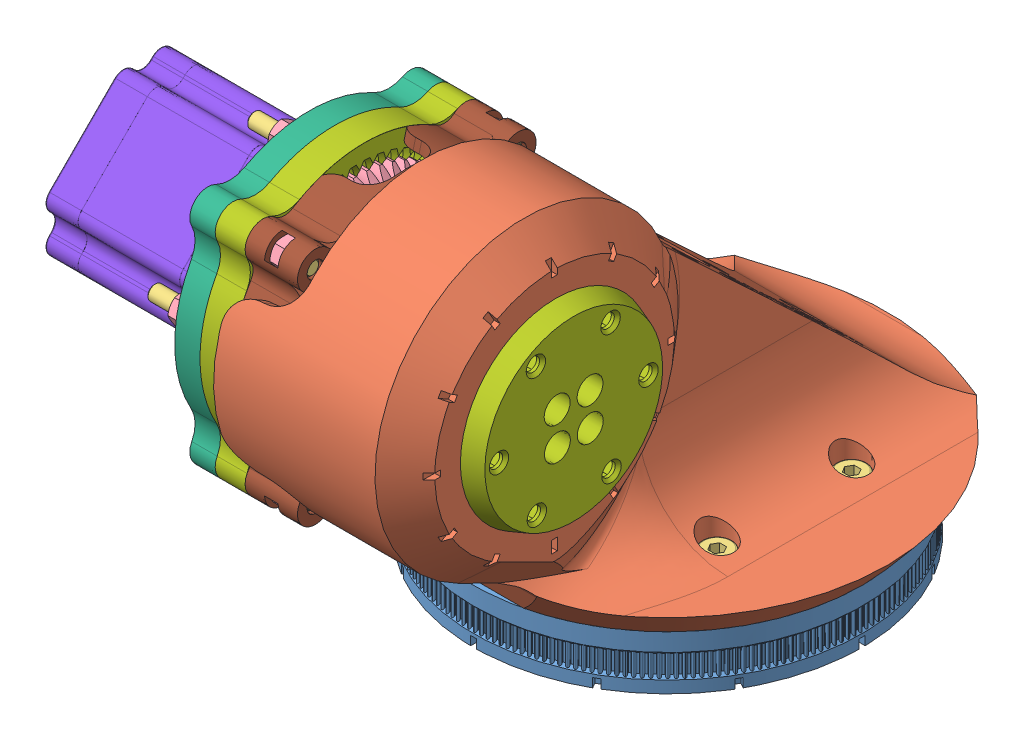
SolidWorks assembly Gelenk_0, configuration Standard. Lengths in mm.
Overall size (179.39 138.2 193.39).
141 component instances, 43 part files, 23 mates.
Components (placement in the parent):
- Base_Arm-1: Base_Arm [Standard] at origin size (130 18.2 130)
- Halterung_Base_Arm-1: Halterung_Base_Arm [Standard] at (0 18 0) size (146.78 120 193.39)
- socket head thin cap screw_din-2: socket head thin cap screw_din [DIN 7984 - M6 x 20 --- 17N] at (-38.9711 27 22.5) x (0 -1 0) z (0 0 1) size (24 10 10)
- hex nut style 1 gradeab_din-1: hex nut style 1 gradeab_din [Hexagon Nut ISO 4032 - M6 - W - N] at (-38.9711 10 22.5) x (1 0 0) z (0 1 0) size (10 11.55 5.2)
- socket head thin cap screw_din-3: socket head thin cap screw_din [DIN 7984 - M6 x 20 --- 17N] at (-38.9711 27 -22.5) x (0 -1 0) z (-0.866025 0 0.5) size (24 10 10)
- socket head thin cap screw_din-4: socket head thin cap screw_din [DIN 7984 - M6 x 20 --- 17N] at (0 27 -45) x (0 -1 0) z (-0.866025 0 -0.5) size (24 10 10)
- socket head thin cap screw_din-5: socket head thin cap screw_din [DIN 7984 - M6 x 20 --- 17N] at (38.9711 27 -22.5) x (0 -1 0) z (0 0 -1) size (24 10 10)
- socket head thin cap screw_din-6: socket head thin cap screw_din [DIN 7984 - M6 x 20 --- 17N] at (38.9711 27 22.5) x (0 -1 0) z (0.866025 0 -0.5) size (24 10 10)
- hex nut style 1 gradeab_din-2: hex nut style 1 gradeab_din [Hexagon Nut ISO 4032 - M6 - W - N] at (-38.9711 10 -22.5) x (0.5 0 0.866025) z (0 1 0) size (10 11.55 5.2)
- hex nut style 1 gradeab_din-3: hex nut style 1 gradeab_din [Hexagon Nut ISO 4032 - M6 - W - N] at (0 10 -45) x (-0.5 0 0.866025) z (0 1 0) size (10 11.55 5.2)
- hex nut style 1 gradeab_din-4: hex nut style 1 gradeab_din [Hexagon Nut ISO 4032 - M6 - W - N] at (38.9711 10 -22.5) x (-1 0 0) z (0 1 0) size (10 11.55 5.2)
- hex nut style 1 gradeab_din-5: hex nut style 1 gradeab_din [Hexagon Nut ISO 4032 - M6 - W - N] at (38.9711 10 22.5) x (-0.5 0 -0.866025) z (0 1 0) size (10 11.55 5.2)
- hex nut style 1 gradeab_din-6: hex nut style 1 gradeab_din [Hexagon Nut ISO 4032 - M3 - W - N] at (12.4 103.5 54.5) x (0 0 -1) z (1 0 0) size (5.5 6.35 2.4)
- radial ball bearing_68_din-1: radial ball bearing_68_din [DIN 625 - 6206 - 12,SI,NC,12_68] at (24 88 70) size (16 62 62)
- Strain_Wave_Base_Finale-1: Strain_Wave_Base_Finale [Standard] at (-50 88 70) x (0 0 1) z (-1 0 0) size (99.02 99.01 139) (flexible)
  - Circular_Spline-1: Circular_Spline [Standard] at origin size (90 90 8.5)
  - Circular_Spline_Teeth-1: Circular_Spline_Teeth [Standard] at (0 0 -12) size (90 90 11.5)
  - Nema_23_56mm-1: Nema_23_56mm [Standard] at (0 0 56) x (0.707107 0.707107 0) z (0 0 -1) size (72.51 57.02 77)
  - Wave_Generator-1: Wave_Generator [Standard] at (0 0 -22.5) size (51.83 63.24 19)
    - Wave_Generator-1: Wave_Generator [Standard] at origin size (49.88 60 10)
    - socket head thin cap screw_din-1: socket head thin cap screw_din [DIN 7984 - M3 x 16 --- 14.5N] at (0 26.62 1) x (0 0 1) z (-1 0 0) size (18 5.5 5.5)
    - socket head thin cap screw_din-2: socket head thin cap screw_din [DIN 7984 - M3 x 16 --- 14.5N] at (11.5 22.98 1) x (0 0 1) z (-1 0 0) size (18 5.5 5.5)
    - socket head thin cap screw_din-3: socket head thin cap screw_din [DIN 7984 - M3 x 16 --- 14.5N] at (19 14.3 1) x (0 0 1) z (-1 0 0) size (18 5.5 5.5)
    - radial ball bearing_68_din-2: radial ball bearing_68_din [DIN 625 - 623 - 8,SI,NC,8_68] at (11.5 22.98 8) x (0 0 -1) z (1 0 0) size (4 10 10)
    - radial ball bearing_68_din-3: radial ball bearing_68_din [DIN 625 - 623 - 8,SI,NC,8_68] at (19 14.3 8) x (0 0 -1) z (1 0 0) size (4 10 10)
    - radial ball bearing_68_din-4: radial ball bearing_68_din [DIN 625 - 623 - 8,SI,NC,8_68] at (0 26.62 8) x (0 0 -1) z (1 0 0) size (4 10 10)
    - Wave_Generator_Case-1: Wave_Generator_Case [Standard] at (0 0 17.5) x (-1 0 0) z (0 0 -1) size (51.83 61 3.5)
    - hex nut style 1 gradeab_din-2: hex nut style 1 gradeab_din [Hexagon Nut ISO 4032 - M3 - W - N] at (0 26.62 17.65) size (5.5 6.35 2.4)
    - hex nut style 1 gradeab_din-3: hex nut style 1 gradeab_din [Hexagon Nut ISO 4032 - M3 - W - N] at (11.5 22.98 17.65) size (5.5 6.35 2.4)
    - hex nut style 1 gradeab_din-4: hex nut style 1 gradeab_din [Hexagon Nut ISO 4032 - M3 - W - N] at (19 14.3 17.65) size (5.5 6.35 2.4)
    - socket head thin cap screw_din-4: socket head thin cap screw_din [DIN 7984 - M3 x 16 --- 14.5N] at (-11.5 22.98 1) x (0 0 1) z (-1 0 0) size (18 5.5 5.5)
    - radial ball bearing_68_din-5: radial ball bearing_68_din [DIN 625 - 623 - 8,SI,NC,8_68] at (-11.5 22.98 8) x (0 0 -1) z (1 0 0) size (4 10 10)
    - hex nut style 1 gradeab_din-5: hex nut style 1 gradeab_din [Hexagon Nut ISO 4032 - M3 - W - N] at (-11.5 22.98 17.65) size (5.5 6.35 2.4)
    - radial ball bearing_68_din-6: radial ball bearing_68_din [DIN 625 - 623 - 8,SI,NC,8_68] at (-19 14.3 8) x (0 0 -1) z (1 0 0) size (4 10 10)
    - hex nut style 1 gradeab_din-6: hex nut style 1 gradeab_din [Hexagon Nut ISO 4032 - M3 - W - N] at (-19 14.3 17.65) size (5.5 6.35 2.4)
    - socket head thin cap screw_din-5: socket head thin cap screw_din [DIN 7984 - M3 x 16 --- 14.5N] at (-19 14.3 1) x (0 0 1) z (-1 0 0) size (18 5.5 5.5)
    - socket head thin cap screw_din-6: socket head thin cap screw_din [DIN 7984 - M3 x 16 --- 14.5N] at (11.5 -22.98 1) x (0 0 1) z (1 0 0) size (18 5.5 5.5)
    - radial ball bearing_68_din-7: radial ball bearing_68_din [DIN 625 - 623 - 8,SI,NC,8_68] at (11.5 -22.98 8) x (0 0 -1) z (-1 0 0) size (4 10 10)
    - hex nut style 1 gradeab_din-7: hex nut style 1 gradeab_din [Hexagon Nut ISO 4032 - M3 - W - N] at (11.5 -22.98 17.65) x (-1 0 0) z (0 0 1) size (5.5 6.35 2.4)
    - radial ball bearing_68_din-8: radial ball bearing_68_din [DIN 625 - 623 - 8,SI,NC,8_68] at (19 -14.3 8) x (0 0 -1) z (-1 0 0) size (4 10 10)
    - hex nut style 1 gradeab_din-8: hex nut style 1 gradeab_din [Hexagon Nut ISO 4032 - M3 - W - N] at (19 -14.3 17.65) x (-1 0 0) z (0 0 1) size (5.5 6.35 2.4)
    - socket head thin cap screw_din-7: socket head thin cap screw_din [DIN 7984 - M3 x 16 --- 14.5N] at (19 -14.3 1) x (0 0 1) z (1 0 0) size (18 5.5 5.5)
    - socket head thin cap screw_din-8: socket head thin cap screw_din [DIN 7984 - M3 x 16 --- 14.5N] at (-11.5 -22.98 1) x (0 0 1) z (1 0 0) size (18 5.5 5.5)
    - radial ball bearing_68_din-9: radial ball bearing_68_din [DIN 625 - 623 - 8,SI,NC,8_68] at (-11.5 -22.98 8) x (0 0 -1) z (-1 0 0) size (4 10 10)
    - hex nut style 1 gradeab_din-9: hex nut style 1 gradeab_din [Hexagon Nut ISO 4032 - M3 - W - N] at (-11.5 -22.98 17.65) x (-1 0 0) z (0 0 1) size (5.5 6.35 2.4)
    - radial ball bearing_68_din-10: radial ball bearing_68_din [DIN 625 - 623 - 8,SI,NC,8_68] at (-19 -14.3 8) x (0 0 -1) z (-1 0 0) size (4 10 10)
    - hex nut style 1 gradeab_din-10: hex nut style 1 gradeab_din [Hexagon Nut ISO 4032 - M3 - W - N] at (-19 -14.3 17.65) x (-1 0 0) z (0 0 1) size (5.5 6.35 2.4)
    - socket head thin cap screw_din-9: socket head thin cap screw_din [DIN 7984 - M3 x 16 --- 14.5N] at (-19 -14.3 1) x (0 0 1) z (1 0 0) size (18 5.5 5.5)
    - socket head thin cap screw_din-10: socket head thin cap screw_din [DIN 7984 - M3 x 16 --- 14.5N] at (0 -26.62 1) x (0 0 1) z (1 0 0) size (18 5.5 5.5)
    - hex nut style 1 gradeab_din-11: hex nut style 1 gradeab_din [Hexagon Nut ISO 4032 - M3 - W - N] at (0 -26.62 17.65) x (-1 0 0) z (0 0 1) size (5.5 6.35 2.4)
    - radial ball bearing_68_din-11: radial ball bearing_68_din [DIN 625 - 623 - 8,SI,NC,8_68] at (0 -26.62 8) x (0 0 -1) z (-1 0 0) size (4 10 10)
    - radial ball bearing_68_din-13: radial ball bearing_68_din [DIN 625 - 623 - 8,SI,NC,8_68] at (11.5 22.98 12) x (0 0 -1) z (1 0 0) size (4 10 10)
    - radial ball bearing_68_din-14: radial ball bearing_68_din [DIN 625 - 623 - 8,SI,NC,8_68] at (19 14.3 12) x (0 0 -1) z (1 0 0) size (4 10 10)
    - radial ball bearing_68_din-15: radial ball bearing_68_din [DIN 625 - 623 - 8,SI,NC,8_68] at (0 26.62 12) x (0 0 -1) z (1 0 0) size (4 10 10)
    - radial ball bearing_68_din-16: radial ball bearing_68_din [DIN 625 - 623 - 8,SI,NC,8_68] at (-11.5 22.98 12) x (0 0 -1) z (1 0 0) size (4 10 10)
    - radial ball bearing_68_din-17: radial ball bearing_68_din [DIN 625 - 623 - 8,SI,NC,8_68] at (-19 14.3 12) x (0 0 -1) z (1 0 0) size (4 10 10)
    - radial ball bearing_68_din-18: radial ball bearing_68_din [DIN 625 - 623 - 8,SI,NC,8_68] at (-19 -14.3 12) x (0 0 -1) z (-1 0 0) size (4 10 10)
    - radial ball bearing_68_din-19: radial ball bearing_68_din [DIN 625 - 623 - 8,SI,NC,8_68] at (-11.5 -22.98 12) x (0 0 -1) z (-1 0 0) size (4 10 10)
    - radial ball bearing_68_din-20: radial ball bearing_68_din [DIN 625 - 623 - 8,SI,NC,8_68] at (0 -26.62 12) x (0 0 -1) z (-1 0 0) size (4 10 10)
    - radial ball bearing_68_din-21: radial ball bearing_68_din [DIN 625 - 623 - 8,SI,NC,8_68] at (11.5 -22.98 12) x (0 0 -1) z (-1 0 0) size (4 10 10)
    - radial ball bearing_68_din-22: radial ball bearing_68_din [DIN 625 - 623 - 8,SI,NC,8_68] at (19 -14.3 12) x (0 0 -1) z (-1 0 0) size (4 10 10)
  - Circular_Spline_Gehaeuse-1: Circular_Spline_Gehaeuse [Standard] at (0 0 -17) size (90 90 41.43)
  - Flex_Spline_Kupplung-1: Flex_Spline_Kupplung [Standard] at (0 0 -35) x (-0.999973 0.0074 0) z (0 0 1) size (60 60 13.5)
  - 06153436-1: 06153436 [Default] at (0 0 -45) x (1 0 0) z (0 -1 0) size (37 7 37)
    - 06153436_01-1: 06153436_01 [Default] at origin size (3.6 3.6 3.6)
    - 06153436_02-1: 06153436_02 [Default] at origin size (3.6 3.6 3.6)
    - 06153436_03-1: 06153436_03 [Default] at origin size (3.6 3.6 3.6)
    - 06153436_04-1: 06153436_04 [Default] at origin size (3.6 3.6 3.6)
    - 06153436_05-1: 06153436_05 [Default] at origin size (3.6 3.6 3.6)
    - 06153436_06-1: 06153436_06 [Default] at origin size (3.6 3.6 3.6)
    - 06153436_07-1: 06153436_07 [Default] at origin size (3.6 3.6 3.6)
    - 06153436_08-1: 06153436_08 [Default] at origin size (3.6 3.6 3.6)
    - 06153436_09-1: 06153436_09 [Default] at origin size (3.6 3.6 3.6)
    - 06153436_10-1: 06153436_10 [Default] at origin size (3.6 3.6 3.6)
    - 06153436_11-1: 06153436_11 [Default] at origin size (3.6 3.6 3.6)
    - 06153436_12-1: 06153436_12 [Default] at origin size (3.6 3.6 3.6)
    - 06153436_13-1: 06153436_13 [Default] at origin size (3.6 3.6 3.6)
    - 06153436_14-1: 06153436_14 [Default] at origin size (3.6 3.6 3.6)
    - 06153436_15-1: 06153436_15 [Default] at origin size (3.6 3.6 3.6)
    - 06153436_16-1: 06153436_16 [Default] at origin size (3.6 3.6 3.6)
    - 06153436_17-1: 06153436_17 [Default] at origin size (3.6 3.6 3.6)
    - 06153436_18-1: 06153436_18 [Default] at origin size (3.6 3.6 3.6)
    - 06153436_19-1: 06153436_19 [Default] at origin size (3.6 3.6 3.6)
    - 06153436_20-1: 06153436_20 [Default] at origin size (3.6 3.6 3.6)
    - 06153436_21-1: 06153436_21 [Default] at origin size (3.6 3.6 3.6)
    - 06153436_22-1: 06153436_22 [Default] at origin size (3.6 3.6 3.6)
    - 06153436_23-1: 06153436_23 [Default] at origin size (3.6 3.6 3.6)
    - 06153436_24-1: 06153436_24 [Default] at origin size (3.6 3.6 3.6)
    - 06153436_25-1: 06153436_25 [Default] at origin size (3.6 3.6 3.6)
    - 06153436_26-1: 06153436_26 [Default] at origin size (29.2 7 29.2)
    - 06153436_27-1: 06153436_27 [Default] at origin size (37 7 37)
  - hex nut style 1 gradeab_din-3: hex nut style 1 gradeab_din [Hexagon Nut ISO 4032 - M3 - W - N] at (15.5 15.5 -50.6) size (5.5 6.35 2.4)
  - Flex_Spline-1: Flex_Spline [Standard] at (0 0 -35) x (-0.493577 0.869702 0) z (0 0 1) size (70 70.08 28)
  - hex nut style 1 gradeab_din-4: hex nut style 1 gradeab_din [Hexagon Nut ISO 4032 - M3 - W - N] at (-0.185 -24.9993 -38.9) x (0.923728 0.383049 0) z (0 0 -1) size (5.5 6.35 2.4)
  - socket head thin cap screw_din-1: socket head thin cap screw_din [DIN 7984 - M3 x 8 --- 6.5N] at (-0.185 -24.9993 -30.5) x (0 0 -1) z (1 0 0) size (10 5.5 5.5)
  - hex nut style 1 gradeab_din-5: hex nut style 1 gradeab_din [Hexagon Nut ISO 4032 - M3 - W - N] at (21.5575 -12.6599 -38.9) x (0.130134 0.991496 0) z (0 0 -1) size (5.5 6.35 2.4)
  - hex nut style 1 gradeab_din-6: hex nut style 1 gradeab_din [Hexagon Nut ISO 4032 - M3 - W - N] at (21.7425 12.3394 -38.9) x (-0.793594 0.608447 0) z (0 0 -1) size (5.5 6.35 2.4)
  - hex nut style 1 gradeab_din-7: hex nut style 1 gradeab_din [Hexagon Nut ISO 4032 - M3 - W - N] at (0.185 24.9993 -38.9) x (-0.923728 -0.383049 0) z (0 0 -1) size (5.5 6.35 2.4)
  - hex nut style 1 gradeab_din-8: hex nut style 1 gradeab_din [Hexagon Nut ISO 4032 - M3 - W - N] at (-21.5575 12.6599 -38.9) x (-0.130134 -0.991496 0) z (0 0 -1) size (5.5 6.35 2.4)
  - hex nut style 1 gradeab_din-9: hex nut style 1 gradeab_din [Hexagon Nut ISO 4032 - M3 - W - N] at (-21.7425 -12.3394 -38.9) x (0.793594 -0.608447 0) z (0 0 -1) size (5.5 6.35 2.4)
  - socket head thin cap screw_din-2: socket head thin cap screw_din [DIN 7984 - M3 x 8 --- 6.5N] at (21.5575 -12.6599 -30.5) x (0 0 -1) z (0.5 0.866025 0) size (10 5.5 5.5)
  - socket head thin cap screw_din-3: socket head thin cap screw_din [DIN 7984 - M3 x 8 --- 6.5N] at (21.7425 12.3394 -30.5) x (0 0 -1) z (-0.5 0.866025 0) size (10 5.5 5.5)
  - socket head thin cap screw_din-4: socket head thin cap screw_din [DIN 7984 - M3 x 8 --- 6.5N] at (0.185 24.9993 -30.5) x (0 0 -1) z (-1 0 0) size (10 5.5 5.5)
  - socket head thin cap screw_din-5: socket head thin cap screw_din [DIN 7984 - M3 x 8 --- 6.5N] at (-21.5575 12.6599 -30.5) x (0 0 -1) z (-0.5 -0.866025 0) size (10 5.5 5.5)
  - socket head thin cap screw_din-6: socket head thin cap screw_din [DIN 7984 - M3 x 8 --- 6.5N] at (-21.7425 -12.3394 -30.5) x (0 0 -1) z (0.5 -0.866025 0) size (10 5.5 5.5)
  - socket head thin cap screw_din-7: socket head thin cap screw_din [DIN 7984 - M6 x 40 --- 18N] at (-5.5406 -5.4591 -39) x (0 0 -1) z (0.052505 0.998621 0) size (44 10 10)
  - Kupplung_StrainWave_Base-1: Kupplung_StrainWave_Base [Standard] at (0 0 -57.2) x (-0.0074 -0.999973 0) z (0 0 1) size (29.7 29.7 8.5)
  - Strain_Wave_Kupplung-2: Strain_Wave_Kupplung [Standard] at (0 0 -48.5) x (-0.0074 -0.999973 0) z (0 0 1) size (29 29 8.7)
  - socket head thin cap screw_din-8: socket head thin cap screw_din [DIN 7984 - M5 x 30 --- 16N] at (33.9411 33.9411 -1.5) x (0 0 -1) z (1 0 0) size (33.5 8.5 8.5)
  - socket head thin cap screw_din-9: socket head thin cap screw_din [DIN 7984 - M5 x 20 --- 17.6N] at (0 33.333 -5) x (0 0 1) z (-1 0 0) size (23.5 8.5 8.5)
  - hex nut style 1 gradeab_din-10: hex nut style 1 gradeab_din [Hexagon Nut ISO 4032 - M5 - D - N] at (0 33.333 9.7) size (8 9.24 4.7)
  - hex nut style 1 gradeab_din-12: hex nut style 1 gradeab_din [Hexagon Nut ISO 4032 - M5 - D - N] at (33.9411 33.9411 -29.7) x (0.923728 0.383049 0) z (0 0 -1) size (8 9.24 4.7)
  - socket head thin cap screw_din-10: socket head thin cap screw_din [DIN 7984 - M6 x 40 --- 18N] at (-5.4591 5.5406 -39) x (0 0 -1) z (0.998621 -0.052505 0) size (44 10 10)
  - socket head thin cap screw_din-11: socket head thin cap screw_din [DIN 7984 - M6 x 40 --- 18N] at (5.5406 5.4591 -39) x (0 0 -1) z (-0.052505 -0.998621 0) size (44 10 10)
  - socket head thin cap screw_din-12: socket head thin cap screw_din [DIN 7984 - M6 x 40 --- 18N] at (5.4591 -5.5406 -39) x (0 0 -1) z (-0.998621 0.052505 0) size (44 10 10)
  - hex nut style 1 gradeab_din-13: hex nut style 1 gradeab_din [Hexagon Nut ISO 4032 - M5 - D - N] at (33.9411 -33.9411 -29.7) x (0.383049 -0.923728 0) z (0 0 -1) size (8 9.24 4.7)
  - hex nut style 1 gradeab_din-14: hex nut style 1 gradeab_din [Hexagon Nut ISO 4032 - M5 - D - N] at (-33.9411 -33.9411 -29.7) x (-0.923728 -0.383049 0) z (0 0 -1) size (8 9.24 4.7)
  - hex nut style 1 gradeab_din-15: hex nut style 1 gradeab_din [Hexagon Nut ISO 4032 - M5 - D - N] at (-33.9411 33.9411 -29.7) x (-0.383049 0.923728 0) z (0 0 -1) size (8 9.24 4.7)
  - socket head thin cap screw_din-13: socket head thin cap screw_din [DIN 7984 - M5 x 30 --- 16N] at (33.9411 -33.9411 -1.5) x (0 0 -1) z (0 -1 0) size (33.5 8.5 8.5)
  - socket head thin cap screw_din-14: socket head thin cap screw_din [DIN 7984 - M5 x 30 --- 16N] at (-33.9411 -33.9411 -1.5) x (0 0 -1) z (-1 0 0) size (33.5 8.5 8.5)
  - socket head thin cap screw_din-15: socket head thin cap screw_din [DIN 7984 - M5 x 30 --- 16N] at (-33.9411 33.9411 -1.5) x (0 0 -1) z (0 1 0) size (33.5 8.5 8.5)
  - hex nut style 1 gradeab_din-16: hex nut style 1 gradeab_din [Hexagon Nut ISO 4032 - M5 - D - N] at (33.333 0 9.7) x (0 -1 0) z (0 0 1) size (8 9.24 4.7)
  - hex nut style 1 gradeab_din-17: hex nut style 1 gradeab_din [Hexagon Nut ISO 4032 - M5 - D - N] at (0 -33.333 9.7) x (-1 0 0) z (0 0 1) size (8 9.24 4.7)
  - hex nut style 1 gradeab_din-18: hex nut style 1 gradeab_din [Hexagon Nut ISO 4032 - M5 - D - N] at (-33.333 0 9.7) x (0 1 0) z (0 0 1) size (8 9.24 4.7)
  - socket head thin cap screw_din-16: socket head thin cap screw_din [DIN 7984 - M5 x 20 --- 17.6N] at (33.333 0 -5) x (0 0 1) z (0 1 0) size (23.5 8.5 8.5)
  - socket head thin cap screw_din-17: socket head thin cap screw_din [DIN 7984 - M5 x 20 --- 17.6N] at (0 -33.333 -5) x (0 0 1) z (1 0 0) size (23.5 8.5 8.5)
  - socket head thin cap screw_din-18: socket head thin cap screw_din [DIN 7984 - M5 x 20 --- 17.6N] at (-33.333 0 -5) x (0 0 1) z (0 -1 0) size (23.5 8.5 8.5)
- socket head thin cap screw_din-8: socket head thin cap screw_din [DIN 7984 - M3 x 12 --- 10.5N] at (1 103.5 54.5) size (14 5.5 5.5)
- hex nut style 1 gradeab_din-7: hex nut style 1 gradeab_din [Hexagon Nut ISO 4032 - M3 - W - N] at (12.4 72.5 54.5) x (0 -1 0) z (1 0 0) size (5.5 6.35 2.4)
- hex nut style 1 gradeab_din-8: hex nut style 1 gradeab_din [Hexagon Nut ISO 4032 - M3 - W - N] at (12.4 72.5 85.5) x (0 0 1) z (1 0 0) size (5.5 6.35 2.4)
- hex nut style 1 gradeab_din-9: hex nut style 1 gradeab_din [Hexagon Nut ISO 4032 - M3 - W - N] at (12.4 103.5 85.5) x (0 1 0) z (1 0 0) size (5.5 6.35 2.4)
- socket head thin cap screw_din-9: socket head thin cap screw_din [DIN 7984 - M3 x 12 --- 10.5N] at (1 72.5 54.5) x (1 0 0) z (0 1 0) size (14 5.5 5.5)
- socket head thin cap screw_din-10: socket head thin cap screw_din [DIN 7984 - M3 x 12 --- 10.5N] at (1 72.5 85.5) x (1 0 0) z (0 0 -1) size (14 5.5 5.5)
- socket head thin cap screw_din-11: socket head thin cap screw_din [DIN 7984 - M3 x 12 --- 10.5N] at (1 103.5 85.5) x (1 0 0) z (0 -1 0) size (14 5.5 5.5)
- Kupplung_Base_2.0-1: Kupplung_Base_2.0 [Standard] at (15.5 88 70) x (0 0.999973 0.0074) z (-1 0 0) size (63.8 63.8 23)
- hex nut style 1 gradeab_din-10: hex nut style 1 gradeab_din [Hexagon Nut ISO 4032 - M6 - W - N] at (0 17.2 -16) x (1 0 0) z (0 1 0) size (10 11.55 5.2)
- hex nut style 1 gradeab_din-11: hex nut style 1 gradeab_din [Hexagon Nut ISO 4032 - M6 - W - N] at (13.8564 17.2 -8) x (0.5 0 0.866025) z (0 1 0) size (10 11.55 5.2)
- hex nut style 1 gradeab_din-12: hex nut style 1 gradeab_din [Hexagon Nut ISO 4032 - M6 - W - N] at (13.8564 17.2 8) x (-0.5 0 0.866025) z (0 1 0) size (10 11.55 5.2)
- hex nut style 1 gradeab_din-13: hex nut style 1 gradeab_din [Hexagon Nut ISO 4032 - M6 - W - N] at (0 17.2 16) x (-1 0 0) z (0 1 0) size (10 11.55 5.2)
- hex nut style 1 gradeab_din-14: hex nut style 1 gradeab_din [Hexagon Nut ISO 4032 - M6 - W - N] at (-13.8564 17.2 8) x (-0.5 0 -0.866025) z (0 1 0) size (10 11.55 5.2)
- hex nut style 1 gradeab_din-15: hex nut style 1 gradeab_din [Hexagon Nut ISO 4032 - M6 - W - N] at (-13.8564 17.2 -8) x (0.5 0 -0.866025) z (0 1 0) size (10 11.55 5.2)
Mates (geometry in assembly coordinates):
- Deckungsgleich1: coincident aligned: plane of Base_Arm-1 through (0 0 0) normal (0 0 1)
- Deckungsgleich2: coincident aligned: plane of Base_Arm-1 through (0 0 0) normal (0 1 0)
- Deckungsgleich3: coincident aligned: plane of Base_Arm-1 through (0 0 0) normal (1 0 0)
- Deckungsgleich4: coincident aligned: circle of Base_Arm-1; circle of Halterung_Base_Arm-1
- Konzentrisch1: concentric aligned: cylinder of Base_Arm-1 through (-38.9711 18 -22.5) axis (0 -1 0) radius 3.25; cylinder of Halterung_Base_Arm-1 through (-38.9711 60 -22.5) axis (0 -1 0) radius 3.25
- Konzentrisch2: concentric anti-aligned: cylinder of Halterung_Base_Arm-1 through (-38.9711 60 22.5) axis (0 -1 0) radius 3.25; cylinder of socket head thin cap screw_din-2 through (-38.9711 58.75 22.5) axis (0 1 0) radius 5
- Deckungsgleich5: coincident anti-aligned: plane of Halterung_Base_Arm-1 through (0 23 0) normal (0 1 0); plane of socket head thin cap screw_din-2 through (-33.9711 23 22.5) normal (0 -1 0)
- Konzentrisch3: concentric aligned: cylinder of socket head thin cap screw_din-2 through (-38.9711 58.75 22.5) axis (0 1 0) radius 3; cylinder of hex nut style 1 gradeab_din-1 through (-38.9711 -15.0375 22.5) axis (0 1 0) radius 3
- Konzentrisch4: concentric anti-aligned: cylinder of Halterung_Base_Arm-1 through (73.391 103.5 54.5) axis (-1 0 0) radius 1.75; cylinder of hex nut style 1 gradeab_din-6 through (-12.6375 103.5 54.5) axis (1 0 0) radius 1.5
- Deckungsgleich6: coincident anti-aligned: plane of Halterung_Base_Arm-1 through (10 18 0) normal (1 0 0); plane of hex nut style 1 gradeab_din-6 through (10 106.6754 54.5) normal (-1 0 0)
- Deckungsgleich7: coincident anti-aligned: plane of Halterung_Base_Arm-1 through (16 88 70) normal (1 0 0); plane of radial ball bearing_68_din-1 through (16 114.2 70) normal (-1 0 0)
- Konzentrisch5: concentric aligned: cylinder of Halterung_Base_Arm-1 through (16 88 70) axis (1 0 0) radius 31.015; cylinder of radial ball bearing_68_din-1 through (3.3625 88 70) axis (1 0 0) radius 31
- Deckungsgleich8: coincident anti-aligned: plane of Halterung_Base_Arm-1 through (8 88 70) normal (-1 0 0); plane of Strain_Wave_Base_Finale-1/Circular_Spline_Gehaeuse-1 through (8 88 70) normal (1 0 0)
- Konzentrisch6: concentric anti-aligned: cylinder of Halterung_Base_Arm-1 through (73.391 103.5 54.5) axis (-1 0 0) radius 1.75; cylinder of Strain_Wave_Base_Finale-1/Circular_Spline_Gehaeuse-1 through (-33 103.5 54.5) axis (1 0 0) radius 1.75
- Konzentrisch7: concentric aligned: cylinder of Halterung_Base_Arm-1 through (32 88 70) axis (-1 0 0) radius 50; cylinder of Strain_Wave_Base_Finale-1/Circular_Spline_Gehaeuse-1 through (-33 88 70) axis (-1 0 0) radius 45
- Konzentrisch8: concentric anti-aligned: cylinder of Strain_Wave_Base_Finale-1/Circular_Spline_Gehaeuse-1 through (-33 103.5 54.5) axis (1 0 0) radius 1.75; cylinder of socket head thin cap screw_din-8 through (-30.75 103.5 54.5) axis (-1 0 0) radius 2.75
- Deckungsgleich10: coincident anti-aligned: plane of Strain_Wave_Base_Finale-1/Circular_Spline_Gehaeuse-1 through (3 88 70) normal (-1 0 0); plane of socket head thin cap screw_din-8 through (3 106.25 54.5) normal (1 0 0)
- Konzentrisch9: concentric anti-aligned: cylinder of radial ball bearing_68_din-1 through (3.3625 88 70) axis (1 0 0) radius 15; cylinder of Kupplung_Base_2.0-1 through (15.5 88 70) axis (-1 0 0) radius 14.95
- Konzentrisch10: concentric aligned: cylinder of Strain_Wave_Base_Finale-1/Kupplung_StrainWave_Base-1 through (7.2 93.5406 64.5409) axis (1 0 0) radius 3.25; cylinder of Kupplung_Base_2.0-1 through (15.5 93.5406 64.5409) axis (1 0 0) radius 3.25
- Deckungsgleich11: coincident anti-aligned: plane of radial ball bearing_68_din-1 through (32 104 70) normal (1 0 0); plane of Kupplung_Base_2.0-1 through (32 88.1106 55.0504) normal (-1 0 0)
- Deckungsgleich12: coincident anti-aligned: plane of Base_Arm-1 through (0 10 0) normal (0 -1 0); plane of hex nut style 1 gradeab_din-4 through (38.9711 10 -16.7265) normal (0 1 0)
- Konzentrisch11: concentric aligned: cylinder of Base_Arm-1 through (0 0 -16) axis (0 1 0) radius 3.25; cylinder of hex nut style 1 gradeab_din-10 through (0 -7.8375 -16) axis (0 1 0) radius 3
- Deckungsgleich13: coincident anti-aligned: plane of Base_Arm-1 through (0 12 0) normal (0 1 0); plane of hex nut style 1 gradeab_din-10 through (0 12 -21.7735) normal (0 -1 0)
